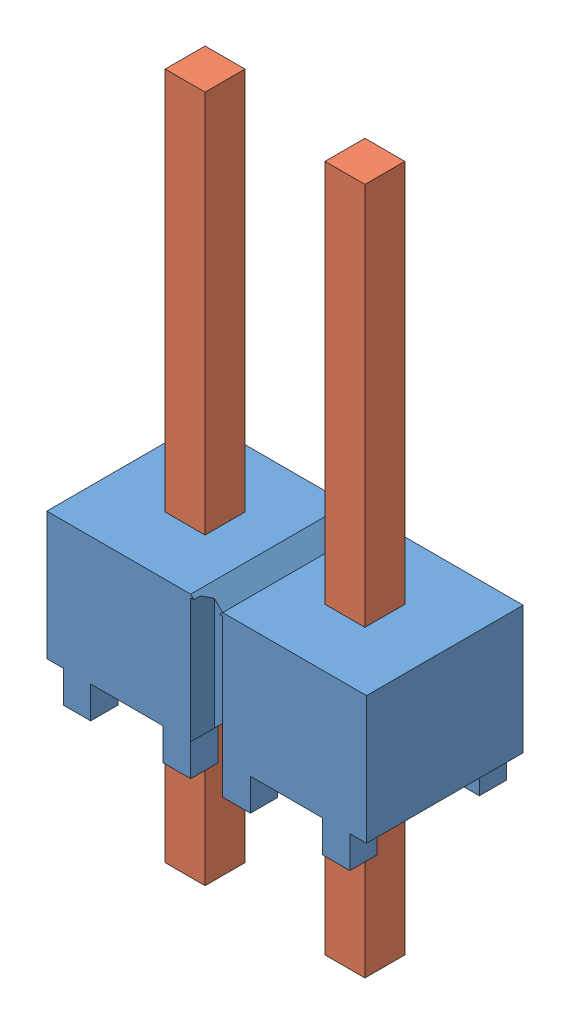
SolidWorks assembly HMTSW_102_07_G_S_240, configuration Default. Lengths in mm.
Overall size (5.08 10.92 2.49).
2 component instances, 2 part files, 0 mates.
Components (placement in the parent):
- _HMTSW_102_07_G_S_240_body_2-1: _HMTSW_102_07_G_S_240_body_2 [Default] at origin size (5.08 2.54 2.49)
- _HMTSW_102_07_S_240_4-1: _HMTSW_102_07_S_240_4 [Default] at (0 -2.286 0) size (3.43 10.92 0.89)
